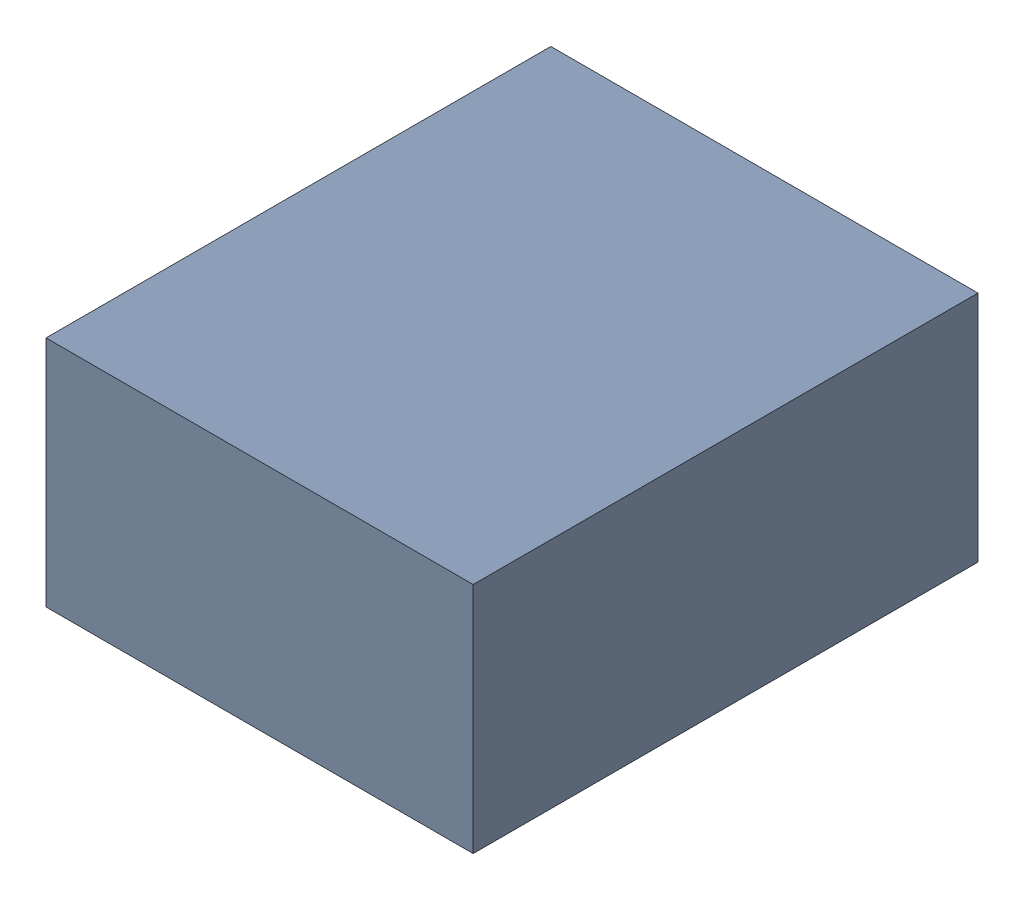
SolidWorks assembly C2, configuration Standard. Lengths in mm.
Overall size (1.1 0.6 1.3).
2 component instances, 1 part files, 0 mates.
Components (placement in the parent):
- 885542240-1: 885542240 [Standard] at (8.85 -4.7 0) size (1.1 0.6 1.3)
  - Extruded_28-1: Extruded_28 [Standard] at origin size (1.1 0.6 1.3)
